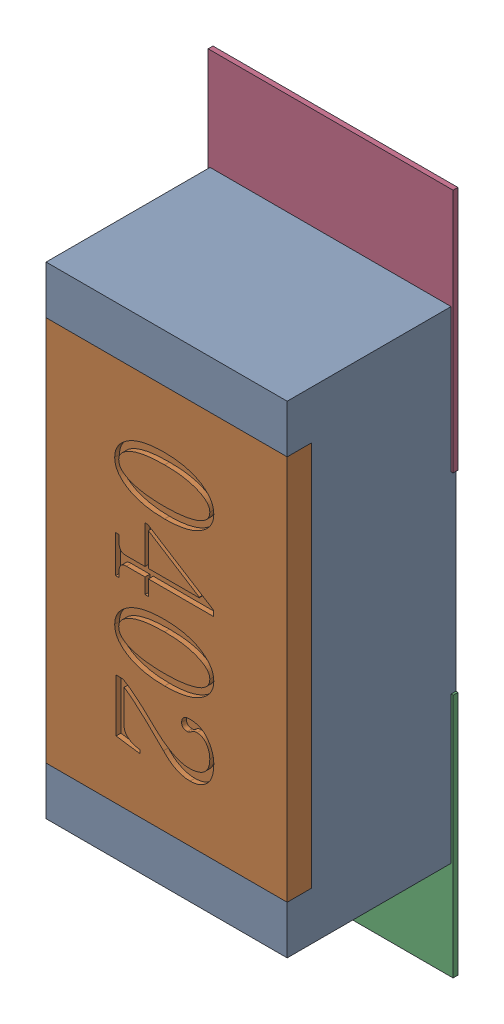
SolidWorks assembly R31, configuration Défaut. Lengths in mm.
Overall size (0.51 1.42 0.35).
5 component instances, 2 part files, 0 mates.
Components (placement in the parent):
- R0402-1: R0402 [Défaut] at (7.9908 -17.0306 0) x (0 -1 0) z (0 0 1) size (1 0.5 0.35)
- 6504207776-1: 6504207776 [Défaut] at (7.991 -17.4806 0) size (0.51 0.51 0.01)
  - Extruded-1: Extruded [Défaut] at origin size (0.51 0.51 0.01)
- 6504207776-2: 6504207776 [Défaut] at (7.991 -16.5735 0) size (0.51 0.51 0.01)
  - Extruded-1: Extruded [Défaut] at origin size (0.51 0.51 0.01)
